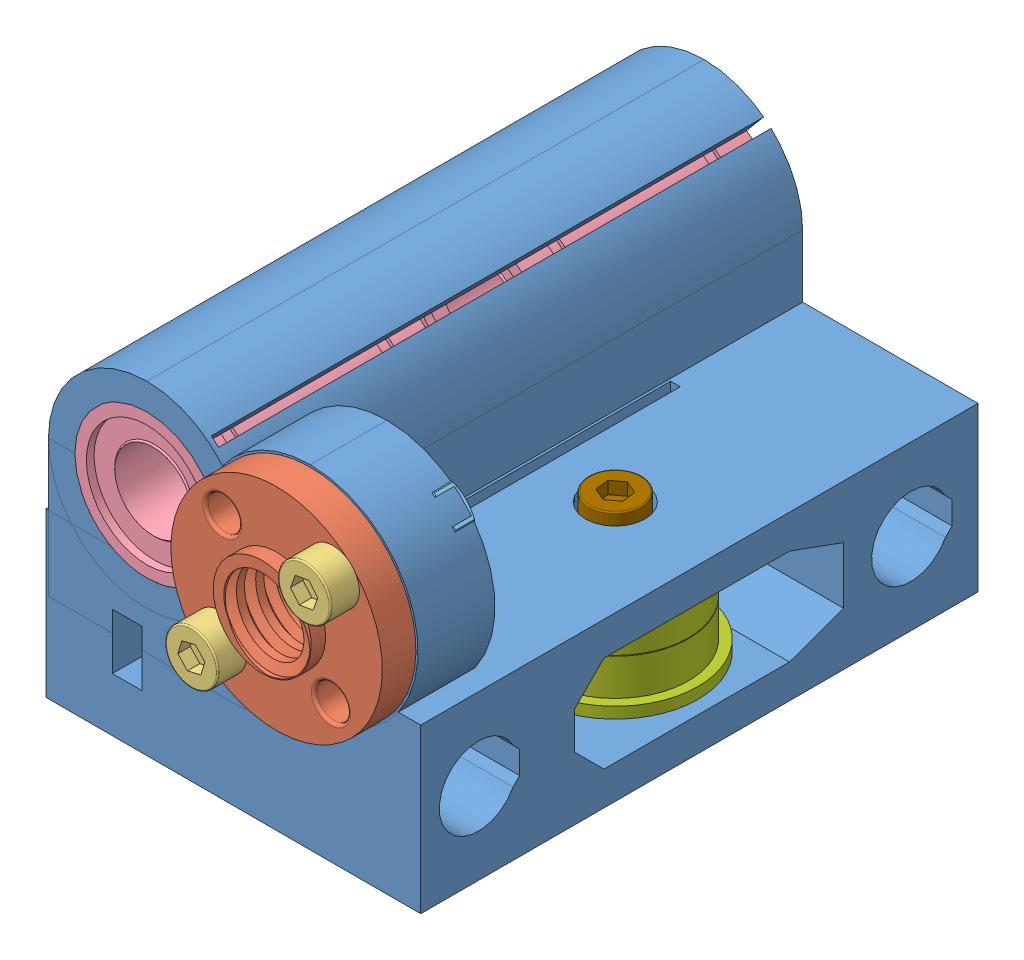
SolidWorks assembly Assembly x-axis right, configuration Valor predeterminado. Lengths in mm.
Overall size (43.97 42.06 64.5).
16 component instances, 9 part files, 33 mates.
Components (placement in the parent):
- x-end-idler-1: x-end-idler [Valor predeterminado] at (10.5 15 0) x (0 1 0) z (0 0 -1) size (34.73 39 58)
- LeadScrew Nut - 8 x 2-1: LeadScrew Nut - 8 x 2 [Default] at (27.5 15 3.5) x (0.707107 -0.707107 0) z (0 0 1) size (22 22 16.05)
- Screw DIN 912 - M3 x 12 --- 12N-1: Screw DIN 912 - M3 x 12 --- 12N [Valor predeterminado] at (33.369 20.869 6.5) x (0 0 1) z (-0.985912 -0.167267 0) size (15 5.5 5.5)
- Screw DIN 912 - M3 x 12 --- 12N-2: Screw DIN 912 - M3 x 12 --- 12N [Valor predeterminado] at (21.631 9.131 6.5) x (0 0 1) z (-0.684286 0.729214 0) size (15 5.5 5.5)
- Linear bearing LM8UU-1: Linear bearing LM8UU [Valor predeterminado] at (11.8237 3.3631 -6.4444) x (0 0 1) z (0.814399 0.580305 0) size (24 15 15)
- Linear bearing LM8UU-2: Linear bearing LM8UU [Valor predeterminado] at (20.7333 9.3036 -40.4444) x (0 0 1) z (0.002099 0.999998 0) size (24 15 15)
- Nut DIN 934 - M3-1: Nut DIN 934 - M3 [Valor predeterminado] at (33.369 20.869 -7.2) x (0 0 1) z (-0.965926 -0.258819 0) size (2.4 5.5 6.35)
- Nut DIN 934 - M3-2: Nut DIN 934 - M3 [Valor predeterminado] at (21.631 9.131 -7.2) x (0 0 1) z (-0.965926 0.258819 0) size (2.4 5.5 6.35)
- Nut DIN 934 - M3-3: Nut DIN 934 - M3 [Valor predeterminado] at (8.1 0 -51) x (1 0 0) z (0 -0.866025 0.5) size (2.4 5.5 6.35)
- Nut DIN 934 - M3-4: Nut DIN 934 - M3 [Valor predeterminado] at (8.1 0 -6) x (-1 0 0) z (0 0 -1) size (2.4 5.5 6.35)
- Assembly belt-guide + bearing-1: Assembly belt-guide + bearing [Valor predeterminado] at (29 0 -30.25) x (0 -1 0) z (-0.872915 0 0.487873) size (10.08 24.25 24.25)
  - Radial ball bearing DIN 625 - 623-1: Radial ball bearing DIN 625 - 623 [Valor predeterminado] at origin size (4 10 10)
  - belt-guide-1: belt-guide [Valor predeterminado] at (5.04 0 0) x (0 -0.638719 0.76944) z (-1 0 0) size (17.22 17.22 5)
  - belt-guide-2: belt-guide [Valor predeterminado] at (-5.04 0 0) x (0 -0.984931 0.17295) z (1 0 0) size (17.22 17.22 5)
- Nut DIN 985 - M3-1: Nut DIN 985 - M3 [Valor predeterminado] at (29 -6.5 -30.25) x (0 1 0) z (-0.5 0 0.866025) size (4 6.35 5.5)
- Screw DIN 912 - M3 x 18 --- 18N-1: Screw DIN 912 - M3 x 18 --- 18N [Valor predeterminado] at (29 9.5 -30.25) x (0 1 0) z (0.802115 0 -0.59717) size (21 5.5 5.5)
Mates (geometry in assembly coordinates):
- Coincidente1: coincident: plane of assembly through (0 0 0) normal (0 0 1); plane of x-end-idler-1 through (39 -8.5 0) normal (0 0 1); plane of assembly
- Coincidente2: coincident: plane of assembly through (0 0 0) normal (1 0 0); plane of x-end-idler-1 through (0 -8.5 0) normal (-1 0 0); plane of assembly
- Simétrico1: symmetric: plane of assembly; plane of assembly; plane of x-end-idler-1 through (43.5 -5 -16) normal (0 1 0); plane of x-end-idler-1 through (43.5 5 -16) normal (0 -1 0); plane of assembly
- Coincidente3: coincident: plane of assembly; plane of assembly; plane of x-end-idler-1 through (19 6.5 0) normal (0.707107 -0.707107 0); plane of LeadScrew Nut - 8 x 2-1 through (27.5 15 3.5) normal (-0.707107 0.707107 0)
- Coincidente4: coincident: plane of assembly; plane of assembly; plane of x-end-idler-1 through (27.5 15 0) normal (0 0 1); plane of LeadScrew Nut - 8 x 2-1 through (27.5 15 0) normal (0 0 -1)
- Concêntrico1: concentric: cylinder of assembly; cylinder of assembly; cylinder of x-end-idler-1 through (27.5 15 1) axis (0 0 -1) radius 5.5555; cylinder of LeadScrew Nut - 8 x 2-1 through (27.5 15 0) axis (0 0 1) radius 11
- Concêntrico2: concentric: cylinder of assembly; cylinder of assembly; cylinder of x-end-idler-1 through (33.369 20.869 1) axis (0 0 -1) radius 1.7; cylinder of Screw DIN 912 - M3 x 12 --- 12N-1 through (33.369 20.869 6.5) axis (0 0 1) radius 1.5
- Coincidente5: coincident: plane of assembly; plane of assembly; plane of LeadScrew Nut - 8 x 2-1 through (27.5 15 3.5) normal (0 0 1); plane of Screw DIN 912 - M3 x 12 --- 12N-1 through (32.909 23.5802 3.5) normal (0 0 -1)
- Concêntrico3: concentric: cylinder of assembly; cylinder of assembly; cylinder of x-end-idler-1 through (21.631 9.131 1) axis (0 0 -1) radius 1.7; cylinder of Screw DIN 912 - M3 x 12 --- 12N-2 through (21.631 9.131 6.5) axis (0 0 1) radius 1.5
- Coincidente6: coincident: plane of assembly; plane of assembly; plane of LeadScrew Nut - 8 x 2-1 through (27.5 15 3.5) normal (0 0 1); plane of Screw DIN 912 - M3 x 12 --- 12N-2 through (23.6364 11.0128 3.5) normal (0 0 -1)
- Concêntrico4: concentric: cylinder of assembly; cylinder of assembly; cylinder of x-end-idler-1 through (10.5 15 1) axis (0 0 -1) radius 7.4933; cylinder of Linear bearing LM8UU-1 through (10.5 15 -12) axis (0 0 1) radius 7.5
- Coincidente7: coincident: plane of assembly; plane of assembly; plane of x-end-idler-1 through (20.75 0.75 0) normal (0 0 1); plane of Linear bearing LM8UU-1 through (5.954 19.3616 0) normal (0 0 1)
- Concêntrico5: concentric: cylinder of assembly; cylinder of assembly; cylinder of x-end-idler-1 through (10.5 15 1) axis (0 0 -1) radius 7.4933; cylinder of Linear bearing LM8UU-2 through (10.5 15 -46) axis (0 0 1) radius 7.5
- Coincidente8: coincident: plane of assembly; plane of assembly; plane of x-end-idler-1 through (10.5 15 -58) normal (0 0 -1); plane of Linear bearing LM8UU-2 through (3.1278 13.6212 -58) normal (0 0 -1)
- Concêntrico6: concentric: cylinder of assembly; cylinder of assembly; cylinder of Screw DIN 912 - M3 x 12 --- 12N-1 through (33.369 20.869 6.5) axis (0 0 1) radius 1.5; cylinder of Nut DIN 934 - M3-1 through (33.369 20.869 -6) axis (0 0 -1) radius 1.25
- Paralelo1: parallel: line of assembly; plane of assembly; line of x-end-idler-1 through (30.1814 20.0149 -8) axis (0.258819 0.965926 0); plane of Nut DIN 934 - M3-1 through (35.6144 18.6236 -6) normal (0.965926 -0.258819 0)
- Coincidente10: coincident: plane of assembly; plane of assembly; plane of x-end-idler-1 through (33.369 20.869 -6) normal (0 0 -1); plane of Nut DIN 934 - M3-1 through (35.6144 18.6236 -6) normal (0 0 1)
- Coincidente11: coincident: plane of assembly; plane of assembly; plane of x-end-idler-1 through (21.4896 8.9896 -6) normal (0 0 -1); plane of Nut DIN 934 - M3-2 through (22.4529 6.0638 -6) normal (0 0 1)
- Paralelo2: parallel: line of assembly; plane of assembly; line of x-end-idler-1 through (20.6614 12.0806 -6) axis (-0.707107 -0.707107 0); plane of Nut DIN 934 - M3-2 through (22.4529 6.0638 -6) normal (0.707107 -0.707107 0)
- Concêntrico7: concentric: cylinder of assembly; cylinder of assembly; cylinder of Screw DIN 912 - M3 x 12 --- 12N-2 through (21.631 9.131 6.5) axis (0 0 1) radius 1.5; cylinder of Nut DIN 934 - M3-2 through (21.631 9.131 -6) axis (0 0 -1) radius 1.25
- Concêntrico8: concentric: cylinder of assembly; cylinder of assembly; cylinder of x-end-idler-1 through (2 0 -6) axis (1 0 0) radius 1.4; cylinder of Nut DIN 934 - M3-4 through (6.9 0 -6) axis (1 0 0) radius 1.25
- Paralelo3: parallel: plane of assembly; plane of assembly; plane of x-end-idler-1 through (10 2.9 6.9) normal (0 -1 0); plane of Nut DIN 934 - M3-4 through (6.9 2.75 -4.4123) normal (0 1 0)
- Concêntrico9: concentric: cylinder of assembly; cylinder of assembly; cylinder of x-end-idler-1 through (2 0 -51) axis (1 0 0) radius 1.4; cylinder of Nut DIN 934 - M3-3 through (9.3 0 -51) axis (-1 0 0) radius 1.25
- Paralelo4: parallel: plane of assembly; plane of assembly; plane of x-end-idler-1 through (10 2.9 -47.4) normal (0 -1 0); plane of Nut DIN 934 - M3-3 through (9.3 2.75 -52.5877) normal (0 1 0)
- Coincidente17: coincident: plane of assembly; plane of assembly; plane of x-end-idler-1 through (6.9 -2.9 -47.4) normal (1 0 0); plane of Nut DIN 934 - M3-3 through (6.9 0 -54.1754) normal (-1 0 0)
- Coincidente18: coincident: plane of assembly; plane of assembly; plane of x-end-idler-1 through (6.9 -2.9 6.9) normal (1 0 0); plane of Nut DIN 934 - M3-4 through (6.9 -2.75 -4.4123) normal (-1 0 0)
- Coincidente19: coincident: plane of Assembly belt-guide + bearing-1/Radial ball bearing DIN 625 - 623-1 through (29 0 -30.25) normal (0 -1 0); plane of assembly through (0 0 0) normal (0 1 0)
- Concêntrico10: concentric: cylinder of assembly; cylinder of assembly; cylinder of x-end-idler-1 through (29 15 -30.25) axis (0 -1 0) radius 1.8; cylinder of Assembly belt-guide + bearing-1/Radial ball bearing DIN 625 - 623-1 through (29 20.6375 -30.25) axis (0 -1 0) radius 1.5
- Concêntrico11: concentric: cylinder of assembly; cylinder of assembly; cylinder of x-end-idler-1 through (29 15 -30.25) axis (0 -1 0) radius 1.8; cylinder of Nut DIN 985 - M3-1 through (29 -14.622 -30.25) axis (0 -1 0) radius 1.25
- Paralelo5: parallel: line of assembly; plane of assembly; line of x-end-idler-1 through (26.1421 -6.5 -28.6) axis (0.866025 0 0.5); plane of Nut DIN 985 - M3-1 through (31.75 -10.5 -31.8377) normal (0.5 0 -0.866025)
- Coincidente21: coincident: plane of assembly; plane of assembly; plane of x-end-idler-1 through (29 -6.5 -30.25) normal (0 -1 0); plane of Nut DIN 985 - M3-1 through (29 -6.5 -30.25) normal (0 1 0)
- Concêntrico14: concentric: cylinder of assembly; cylinder of assembly; cylinder of x-end-idler-1 through (29 15 -30.25) axis (0 -1 0) radius 1.8; cylinder of Screw DIN 912 - M3 x 18 --- 18N-1 through (29 9.5 -30.25) axis (0 1 0) radius 1.5
- Coincidente24: coincident: plane of assembly; plane of assembly; plane of x-end-idler-1 through (29 6.5 -30.25) normal (0 1 0); plane of Screw DIN 912 - M3 x 18 --- 18N-1 through (30.6422 6.5 -28.0442) normal (0 -1 0)
